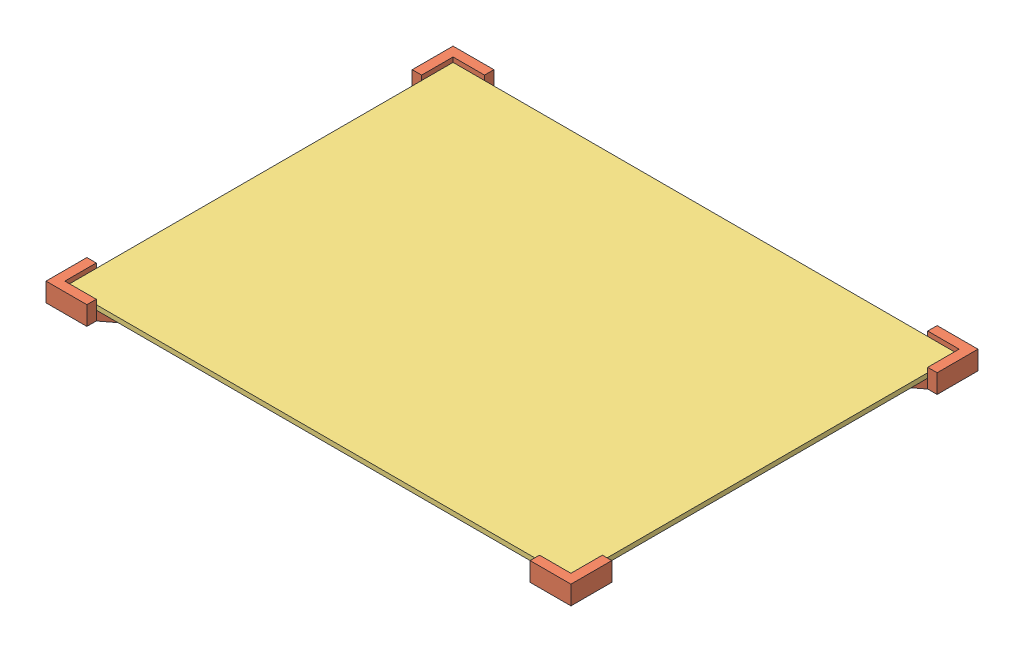
SolidWorks assembly Ensamblaje2, configuration Predeterminado. Lengths in mm.
Overall size (334 30 259).
3 component instances, 3 part files, 6 mates.
Components (placement in the parent):
- Efector_Final-1: Efector_Final [Predeterminado] at (25.1757 -47.7917 129.2098) size (122.44 12 106.04)
- Base_Pantalla-1: Base_Pantalla [Predeterminado] at (25.1757 -29.7917 129.2098) size (334 30 259)
- Pantalla-1: Pantalla [Predeterminado] at (25.1757 -23.7917 129.2098) size (322 3 247)
Mates (geometry in assembly coordinates):
- Concéntrica1: concentric: cylinder of assembly; cylinder of assembly; cylinder of Efector_Final-1 through (25.1757 -35.7917 129.2098) axis (0 -1 0) radius 28.75; cylinder of Base_Pantalla-1 through (25.1757 -41.7917 129.2098) axis (0 1 0) radius 28.25
- Paralelo1: parallel: plane of assembly; plane of assembly; plane of Efector_Final-1 through (-3.5743 -35.7917 107.9598) normal (0 0 1); plane of Base_Pantalla-1 through (38.4257 -41.7917 150.2098) normal (0 0 1)
- Coincidente2: coincident: plane of assembly; plane of assembly; plane of Efector_Final-1 through (25.1757 -35.7917 129.2098) normal (0 1 0); plane of Base_Pantalla-1 through (25.1757 -35.7917 129.2098) normal (0 -1 0)
- Coincidente3: coincident: line of assembly; line of assembly; line of Base_Pantalla-1 through (-135.8243 -17.7917 5.7098) axis (0 -1 0); line of Pantalla-1 through (-135.8243 -20.7917 5.7098) axis (0 -1 0)
- Coincidente4: coincident: line of assembly; line of assembly; line of Base_Pantalla-1 through (186.1757 -17.7917 252.7098) axis (0 -1 0); line of Pantalla-1 through (186.1757 -20.7917 252.7098) axis (0 -1 0)
- Coincidente5: coincident: plane of assembly; plane of assembly; plane of Base_Pantalla-1 through (25.1757 -23.7917 129.2098) normal (0 1 0); plane of Pantalla-1 through (25.1757 -23.7917 129.2098) normal (0 -1 0)
